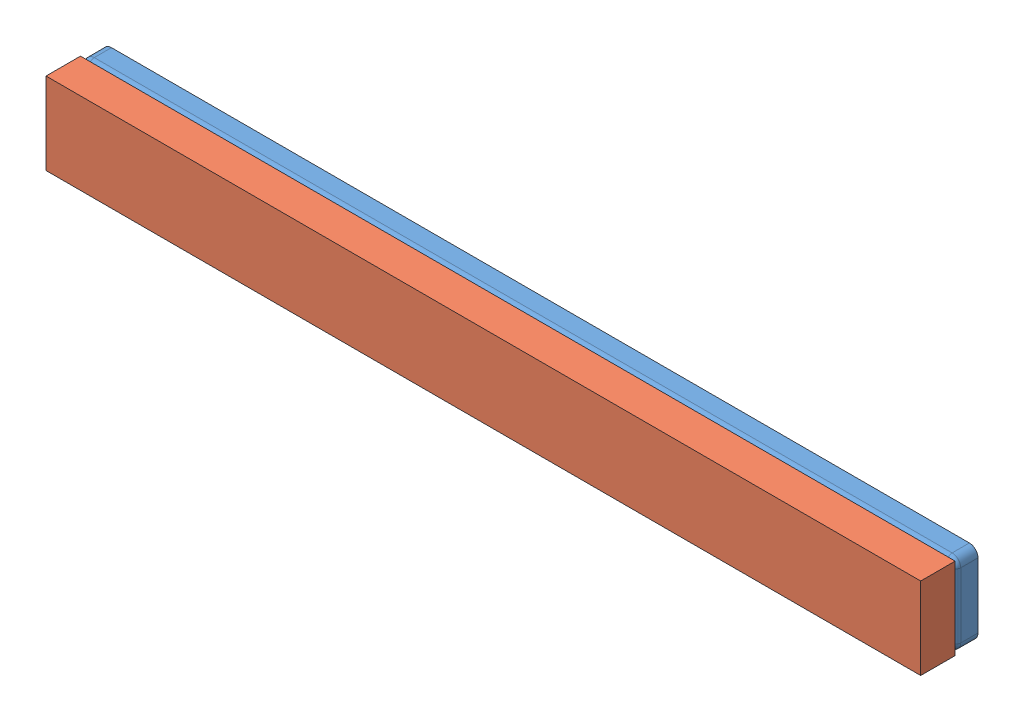
SolidWorks assembly Assem206, configuration Default. Lengths in mm.
Overall size (108.66 20.13 13.01).
2 component instances, 2 part files, 3 mates.
Components (placement in the parent):
- camera-1: camera [Default] at (89.5051 39.5229 69.2524) size (108.66 20.13 13.01)
- cover-1: cover [Default] at (28.5501 44.2729 69.9074) x (-1 0 0) z (0 -1 0) size (101.5 4 9.5)
Mates (geometry in assembly coordinates):
- Coincident1: coincident aligned: plane of camera-1 through (28.5751 44.2979 65.9074) normal (0 0 -1); plane of cover-1 through (28.5501 44.2729 65.9074) normal (0 0 -1)
- Coincident2: coincident anti-aligned: plane of camera-1 through (-22.1999 39.5229 65.9074) normal (0 1 0); plane of cover-1 through (79.3001 39.5229 65.9074) normal (0 -1 0)
- Coincident3: coincident anti-aligned: plane of camera-1 through (-22.1999 49.0729 65.9074) normal (1 0 0); plane of cover-1 through (-22.1999 49.0229 65.9074) normal (-1 0 0)
